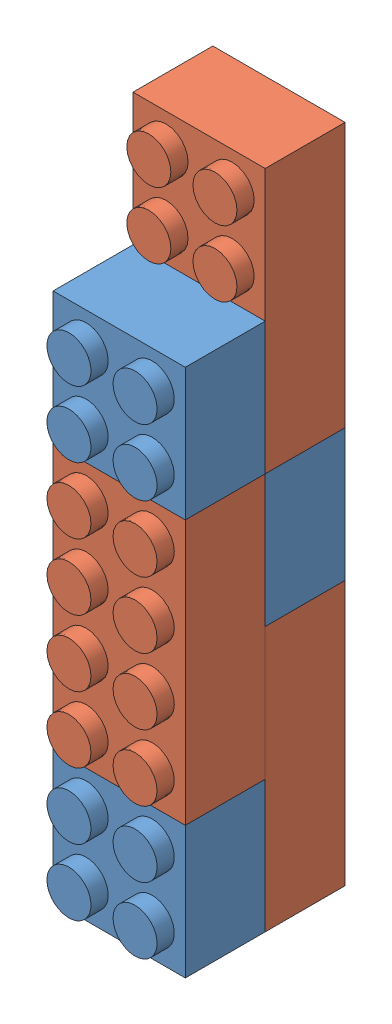
SolidWorks assembly Assemblage1, configuration Défaut. Lengths in mm.
Overall size (96 480 128.5).
6 component instances, 2 part files, 15 mates.
Components (placement in the parent):
- base_lego_2x2-1: base_lego_2x2 [Défaut] at (-139.8071 36.213 96) size (96 96 70.5)
- base_lego_2x4-1: base_lego_2x4 [Défaut] at (-187.8071 -203.787 96) size (96 192 70.5)
- base_lego_2x4-2: base_lego_2x4 [Défaut] at (-187.8071 -107.787 154) size (96 192 70.5)
- base_lego_2x2-2: base_lego_2x2 [Défaut] at (-139.8071 -155.787 154) size (96 96 70.5)
- base_lego_2x4-3: base_lego_2x4 [Défaut] at (-187.8071 84.213 96) size (96 192 70.5)
- base_lego_2x2-3: base_lego_2x2 [Défaut] at (-139.8071 132.213 154) size (96 96 70.5)
Mates (geometry in assembly coordinates):
- Coïncidente1: coincident: plane of base_lego_2x2-1 through (-91.8071 -11.787 144) normal (0 -1 0); plane of base_lego_2x4-1 through (-187.8071 -11.787 144) normal (0 1 0)
- Coïncidente2: coincident: plane of base_lego_2x2-1 through (-187.8071 -11.787 144) normal (-1 0 0); plane of base_lego_2x4-1 through (-187.8071 -107.787 144) normal (-1 0 0)
- Coïncidente3: coincident: plane of base_lego_2x2-1 through (-139.8071 36.213 96) normal (0 0 -1); plane of base_lego_2x4-1 through (-139.8071 -59.787 96) normal (0 0 -1)
- Coïncidente4: coincident: plane of base_lego_2x4-1 through (-187.8071 -107.787 144) normal (-1 0 0); plane of base_lego_2x4-2 through (-187.8071 -11.787 202) normal (-1 0 0)
- Coïncidente5: coincident: plane of base_lego_2x2-1 through (-187.8071 84.213 144) normal (0 1 0); plane of base_lego_2x4-2 through (-187.8071 84.213 202) normal (0 1 0)
- Coïncidente8: coincident: plane of base_lego_2x4-1 through (-139.8071 -59.787 154) normal (0 0 1); plane of base_lego_2x4-2 through (-139.8071 -59.787 154) normal (0 0 -1)
- Coïncidente9: coincident: plane of base_lego_2x4-1 through (-187.8071 -107.787 144) normal (-1 0 0); plane of base_lego_2x2-2 through (-187.8071 -203.787 202) normal (-1 0 0)
- Coïncidente10: coincident: plane of base_lego_2x4-1 through (-139.8071 -59.787 154) normal (0 0 1); plane of base_lego_2x2-2 through (-139.8071 -155.787 154) normal (0 0 -1)
- Coïncidente11: coincident: plane of base_lego_2x4-2 through (-91.8071 -107.787 202) normal (0 -1 0); plane of base_lego_2x2-2 through (-187.8071 -107.787 202) normal (0 1 0)
- Coïncidente12: coincident: plane of base_lego_2x2-1 through (-187.8071 84.213 144) normal (0 1 0); plane of base_lego_2x4-3 through (-91.8071 84.213 144) normal (0 -1 0)
- Coïncidente13: coincident: plane of base_lego_2x2-1 through (-187.8071 -11.787 144) normal (-1 0 0); plane of base_lego_2x4-3 through (-187.8071 180.213 144) normal (-1 0 0)
- Coïncidente14: coincident: plane of base_lego_2x2-1 through (-139.8071 36.213 96) normal (0 0 -1); plane of base_lego_2x4-3 through (-139.8071 228.213 96) normal (0 0 -1)
- Coïncidente15: coincident: plane of base_lego_2x4-2 through (-187.8071 84.213 202) normal (0 1 0); plane of base_lego_2x2-3 through (-91.8071 84.213 202) normal (0 -1 0)
- Coïncidente16: coincident: plane of base_lego_2x4-2 through (-187.8071 -11.787 202) normal (-1 0 0); plane of base_lego_2x2-3 through (-187.8071 84.213 202) normal (-1 0 0)
- Coïncidente17: coincident: plane of base_lego_2x4-3 through (-139.8071 228.213 154) normal (0 0 1); plane of base_lego_2x2-3 through (-139.8071 132.213 154) normal (0 0 -1)
